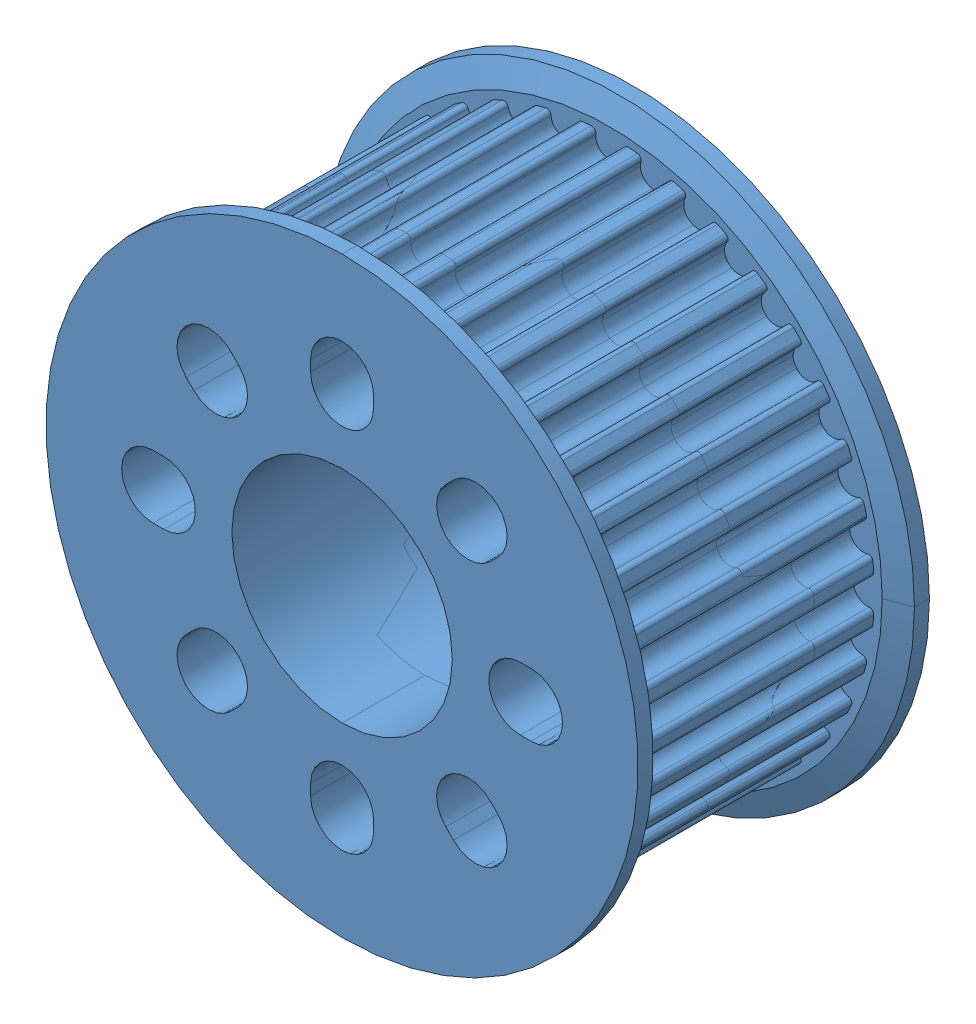
SolidWorks assembly 36 tooth 3mm pitch belt pulley 3402-0014-0036, configuration Default. Lengths in mm.
Overall size (37.6 37.6 18.5).
2 component instances, 1 part files, 3 mates.
Components (placement in the parent):
- 36 tooth 3mm pitch belt pulley-1: 36 tooth 3mm pitch belt pulley [Default] at origin size (37.6 37.6 13.25)
- 36 tooth 3mm pitch belt pulley-2: 36 tooth 3mm pitch belt pulley [Default] at (0 0 -5.1) x (0 -1 0) z (0 0 -1) size (37.6 37.6 13.25)
Mates (geometry in assembly coordinates):
- Concentric1: concentric: cylinder of 36 tooth 3mm pitch belt pulley-1 through (0 0 -2.55) axis (0 0 -1) radius 7; cylinder of 36 tooth 3mm pitch belt pulley-2 through (0 0 -2.55) axis (0 0 1) radius 7
- Coincident1: coincident: plane of 36 tooth 3mm pitch belt pulley-1 through (-18.8 0 -6.55) normal (0 0 1); plane of 36 tooth 3mm pitch belt pulley-2 through (0 0 -6.55) normal (0 0 -1)
- Coincident2: coincident anti-aligned: plane of 36 tooth 3mm pitch belt pulley-1 through (-18.8 4.7932 -1.7446) normal (0 -0.939693 0.34202); plane of 36 tooth 3mm pitch belt pulley-2
